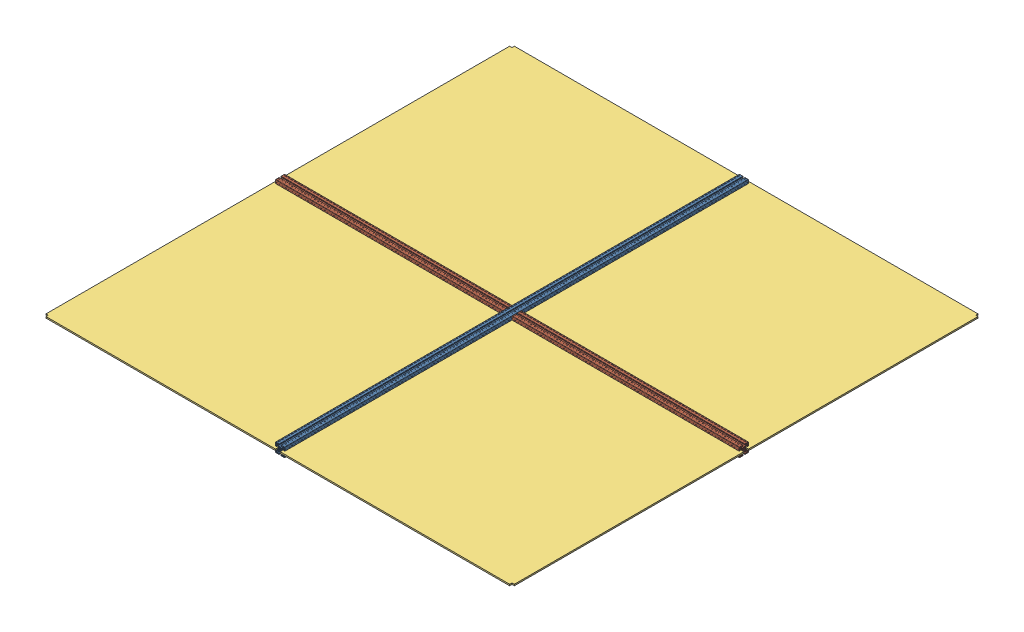
SolidWorks assembly Teto_Mod_Clean, configuration Valor predeterminado. Lengths in mm.
Overall size (2020 40 2020).
7 component instances, 3 part files, 14 mates.
Components (placement in the parent):
- Perfil_Alum_4x4x200-1: Perfil_Alum_4x4x200 [Valor predeterminado] at (-262.3542 -2000 -6.7617) size (40 40 2000)
- Perfil_Alum_4x4x98-1: Perfil_Alum_4x4x98 [Valor predeterminado] at (-772.3542 -2000 -6.7617) x (0 0 -1) z (1 0 0) size (40 40 980)
- Perfil_Alum_4x4x98-2: Perfil_Alum_4x4x98 [Valor predeterminado] at (247.6458 -2000 -6.7617) x (0 0 -1) z (1 0 0) size (40 40 980)
- Policarbonato_Teto-1: Policarbonato_Teto [Valor predeterminado] at (-772.3542 -2000 -516.7617) size (1000 6 1000)
- Policarbonato_Teto-2: Policarbonato_Teto [Valor predeterminado] at (-772.3542 -2000 503.2383) x (0 0 -1) z (1 0 0) size (1000 6 1000)
- Policarbonato_Teto-3: Policarbonato_Teto [Valor predeterminado] at (247.6458 -2000 503.2383) x (-1 0 0) z (0 0 -1) size (1000 6 1000)
- Policarbonato_Teto-4: Policarbonato_Teto [Valor predeterminado] at (247.6458 -2000 -516.7617) x (0 0 1) z (-1 0 0) size (1000 6 1000)
Mates (geometry in assembly coordinates):
- Distância1: distance = 980 mm: line of Perfil_Alum_4x4x98-2 through (-242.3542 -2014.4 13.2383) axis (0 -1 0); line of Perfil_Alum_4x4x200-1 through (-242.3542 -2018.5 993.2383) axis (0 1 0)
- Distância2: distance = 980 mm: line of Perfil_Alum_4x4x98-1 through (-282.3542 -2014.4 13.2383) axis (0 -1 0); line of Perfil_Alum_4x4x200-1 through (-282.3542 -2014.4 993.2383) axis (0 -1 0)
- Coincidente1: coincident anti-aligned: plane of Perfil_Alum_4x4x98-1 through (-282.3542 -2005.1005 3.2383) normal (0 0 1); plane of Policarbonato_Teto-2 through (-1272.3542 -1997 3.2383) normal (0 0 -1)
- Coincidente2: coincident anti-aligned: plane of Perfil_Alum_4x4x200-1 through (-272.3542 -2005.1005 993.2383) normal (-1 0 0); plane of Policarbonato_Teto-2 through (-272.3542 -1997 1003.2383) normal (1 0 0)
- Distância3: distance = 1.15 mm anti-aligned: plane of Perfil_Alum_4x4x200-1 through (-281.1542 -2004.15 993.2383) normal (0 1 0); plane of Policarbonato_Teto-2 through (-772.3542 -2003 503.2383) normal (0 -1 0)
- Coincidente4: coincident anti-aligned: plane of Perfil_Alum_4x4x98-1 through (-282.3542 -1994.8995 -16.7617) normal (0 0 -1); plane of Policarbonato_Teto-1 through (-1272.3542 -1997 -16.7617) normal (0 0 1)
- Coincidente5: coincident anti-aligned: plane of Perfil_Alum_4x4x200-1 through (-272.3542 -2005.1005 993.2383) normal (-1 0 0); plane of Policarbonato_Teto-1 through (-272.3542 -1997 -1016.7617) normal (1 0 0)
- Distância4: distance = 1.15 mm anti-aligned: plane of Perfil_Alum_4x4x200-1 through (-278.2542 -1995.85 993.2383) normal (0 -1 0); plane of Policarbonato_Teto-1 through (-772.3542 -1997 -516.7617) normal (0 1 0)
- Coincidente7: coincident: plane of Perfil_Alum_4x4x98-2 through (737.6458 -2005.1005 3.2383) normal (0 0 1); plane of Policarbonato_Teto-3 through (747.6458 -1997 3.2383) normal (0 0 -1)
- Coincidente8: coincident: plane of Perfil_Alum_4x4x200-1 through (-252.3542 -1994.8995 993.2383) normal (1 0 0); plane of Policarbonato_Teto-3 through (-252.3542 -1997 1003.2383) normal (-1 0 0)
- Distância5: distance = 1.15 mm anti-aligned: plane of Perfil_Alum_4x4x200-1 through (-243.5542 -1995.85 993.2383) normal (0 -1 0); plane of Policarbonato_Teto-3 through (247.6458 -1997 503.2383) normal (0 1 0)
- Coincidente10: coincident: plane of Perfil_Alum_4x4x200-1 through (-252.3542 -1994.8995 993.2383) normal (1 0 0); plane of Policarbonato_Teto-4 through (-252.3542 -1997 -1016.7617) normal (-1 0 0)
- Coincidente11: coincident: plane of Perfil_Alum_4x4x98-2 through (737.6458 -1994.8995 -16.7617) normal (0 0 -1); plane of Policarbonato_Teto-4 through (747.6458 -1997 -16.7617) normal (0 0 1)
- Distância6: distance = 1.15 mm anti-aligned: plane of Perfil_Alum_4x4x98-2 through (737.6458 -1995.85 -25.5617) normal (0 -1 0); plane of Policarbonato_Teto-4 through (247.6458 -1997 -516.7617) normal (0 1 0)
